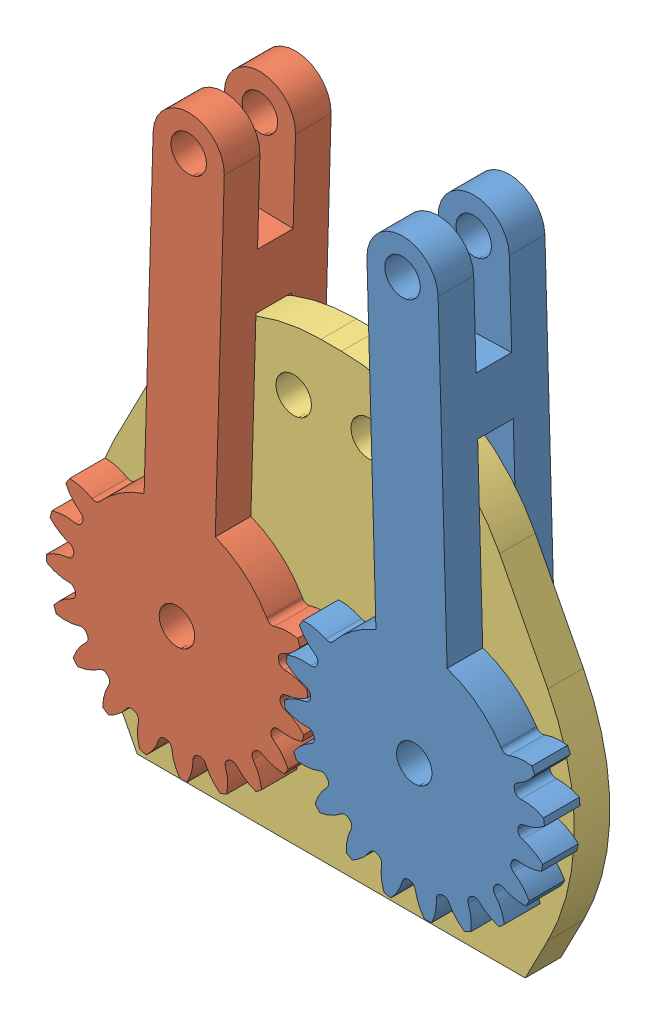
SolidWorks assembly Base+ruote, configuration Default. Lengths in mm.
Overall size (42.58 52.3 9).
3 component instances, 3 part files, 7 mates.
Components (placement in the parent):
- Link 1 Sinistro-1: Link 1 Sinistro [Default] at (24.0054 -9.1761 8.8122) x (-0.028306 0.999599 0) z (0 0 1) size (48.99 21.97 9)
- Link 1 Destro-1: Link 1 Destro [Default] at (4.0046 -9.1761 8.8122) x (0.028306 0.999599 0) z (0 0 1) size (48.99 21.97 9)
- Base 2-1: Base 2 [Default] at (24.0054 -9.1761 7.3122) size (40.97 38 3)
Mates (geometry in assembly coordinates):
- Concentrico2: concentric anti-aligned: cylinder of Link 1 Sinistro-1 through (24.0054 -9.1761 4.3122) axis (0 0 1) radius 1.5; cylinder of Base 2-1 through (24.0054 -9.1761 10.3122) axis (0 0 -1) radius 1.5
- Coincidente1: coincident anti-aligned: plane of Link 1 Sinistro-1 through (6.3452 -21.4309 10.3122) normal (0 0 -1); plane of Base 2-1 through (24.0054 -9.1761 10.3122) normal (0 0 1)
- Concentrico3: concentric anti-aligned: cylinder of Link 1 Destro-1 through (4.0046 -9.1761 4.3122) axis (0 0 1) radius 1.5; cylinder of Base 2-1 through (4.0046 -9.1761 10.3122) axis (0 0 -1) radius 1.5
- Coincidente2: coincident anti-aligned: plane of Link 1 Destro-1 through (-14.3208 -20.4119 10.3122) normal (0 0 -1); plane of Base 2-1 through (24.0054 -9.1761 10.3122) normal (0 0 1)
- Parallelo3: parallel anti-aligned: line of Link 1 Destro-1 through (-4.215 -12.1761 13.3122) axis (-1 0 0); line of Base 2-1 through (-2.3447 -23.1761 10.3122) axis (1 0 0)
- Parallelo4: parallel aligned: line of Link 1 Sinistro-1 through (32.225 -12.1761 13.3122) axis (1 0 0); line of Base 2-1 through (-2.3447 -23.1761 10.3122) axis (1 0 0)
- AccoppiaIngranaggi1: gear = 3 : 3 mm: cylinder of Link 1 Destro-1 through (4.0046 -9.1761 4.3122) axis (0 0 1) radius 1.5; cylinder of Link 1 Sinistro-1 through (24.0054 -9.1761 4.3122) axis (0 0 1) radius 1.5
